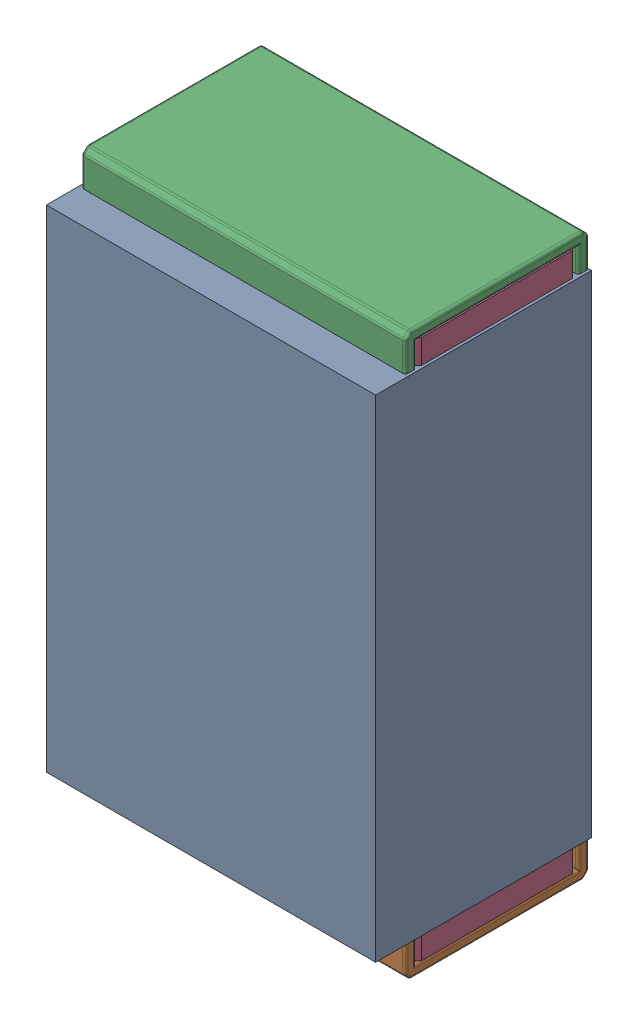
SolidWorks assembly R17, configuration Default. Lengths in mm.
Overall size (0.61 1.04 0.4).
3 component instances, 2 part files, 0 mates.
Components (placement in the parent):
- 1088881848-1: 1088881848 [Default] at (15.725 2.4 0) size (0.61 0.91 0.4)
  - Extruded-1-1: Extruded-1 [Default] at origin size (0.61 0.91 0.4)
- R0402-1: R0402 [Default] at (15.725 2.3999 0) x (0 -1 0) z (-1 0 0) size (1.04 0.34 0.6)
